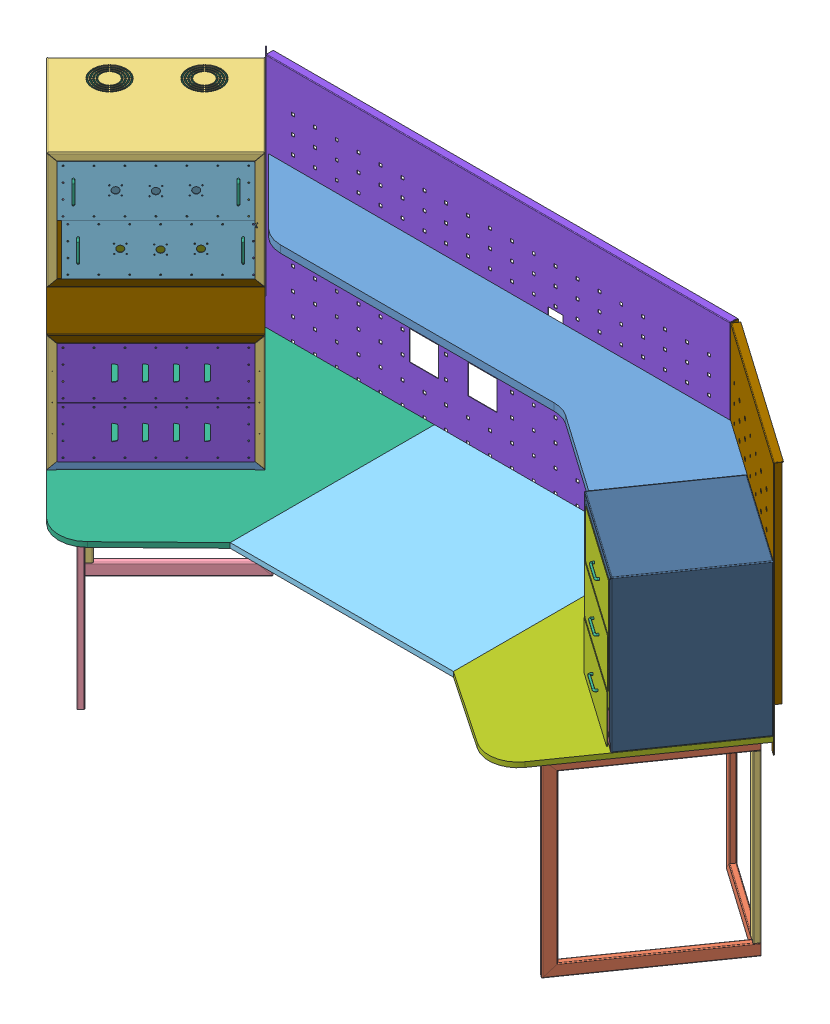
SolidWorks assembly ghép tổng, configuration Default. Lengths in mm.
Overall size (2623.8 1517 999.25).
65 component instances, 44 part files, 69 mates.
Components (placement in the parent):
- Assem chan trái-1: Assem chan trái [Default] at (-139.3246 124.9655 -27.3577) size (1329.02 40 864.99)
  - mặt bàn số 1-2: mặt bàn số 1 [Default<As Machined>] at (-327.0001 624.1073 994.183) size (1329.02 40 864.99)
  - ong giưa-4: ong giưa [Default<As Machined>] at (444.6829 644.1073 947.4494) x (0 0 1) z (-1 0 0) size (550 40 20)
- khung trái-1: khung trái [Default] at (-381.393 516.0492 385.0257) x (0 -1 0) z (-0.707107 0 0.707107) size (650 580 475)
  - ống chân-1: ống chân [Default<As Machined>] at (-193.0236 341.3386 471.4503) size (570 20 40)
  - chân số 1-1: chân số 1 [Default<As Machined>] at (376.9764 351.3386 471.4503) x (0 1 0) z (0 0 1) size (580 650 475)
- mặt bàn gỗ 1-2: mặt bàn gỗ 1 [Default] at (485.069 789.0728 1276.2616) size (765 17 700)
- mặt gỗ trái-2: mặt gỗ trái [Default] at (389.532 789.0728 1325.0917) size (954.77 17 970.55)
- mặt gỗ phải-2: mặt gỗ phải [Default] at (1154.532 789.0728 1325.0917) size (741.49 17 887.84)
- mặt sau trên-3: mặt sau trên [Default] at (607.032 749.0728 623.5917) x (-1 0 0) z (0 0 -1) size (1618.25 867 25.81)
- mặt phải tren-2: mặt phải tren [Default] at (1649.1305 749.0728 796.3614) x (0.819152 0 0.573576) z (-0.573576 0 0.819152) size (612.94 867 25)
- tủ phải chuan-2: tủ phải chuan [Default] at (2052.0607 760.4203 1059.043) x (-0.573576 0 0.819152) z (-0.819152 0 -0.573576) size (400 520 370)
  - ghép 1-1: ghép 1 [Default] at (144.53 45.6525 549.3287) size (400 520 370)
  - ghép 1 sau-1: ghép 1 sau [Default] at (15.935 45.6525 524.3287) x (0 0 -1) z (1 0 0) size (320 70 25)
  - doc phai-1: doc phai [Default] at (17.435 47.1525 180.8287) size (50 512 35)
  - ghep trước-5: ghep trước [Default] at (414.435 45.6525 549.3287) x (0 0 -1) z (1 0 0) size (370 25 25)
  - doc trai-1: doc trai [Default] at (17.435 559.1525 547.8287) x (1 0 0) z (0 0 -1) size (50 512 35)
  - doc trai  2-1: doc trai  2 [Default] at (414.435 47.1525 547.8287) x (-1 0 0) z (0 0 -1) size (50 514 35)
  - doc phai 2y-2: doc phai 2y [Default] at (414.435 561.1525 180.8287) x (-1 0 0) z (0 0 1) size (50 514 35)
  - nap sau-1: nap sau [Default] at (17.435 115.6525 364.3287) x (0 0 -1) z (1 0 0) size (320 370 10)
- Ghép tủ trái-1: Ghép tủ trái [Default] at (419.7096 736.1847 1334.931) x (-0.707107 0 0.707107) z (-0.707107 0 -0.707107) size (530 800 600)
  - tủ bên trái-1: tủ bên trái [Default] at (-46.2827 78.451 -28.8757) size (530 800 600)
    - năp hop ben trai-1: năp hop ben trai [Default] at (240.8112 391.4371 463.2686) x (-1 0 0) z (0 -1 0) size (530 202 48.5)
    - thanh nap truoc-1: thanh nap truoc [Default] at (505.8112 16.4371 362.2686) x (-1 0 0) z (0 0 1) size (530 25 25)
    - thanh nap sau-1: thanh nap sau [Default] at (0.8112 61.4371 962.2686) x (1 0 0) z (0 0 -1) size (480 70 25)
    - Tủ bên trái 29x9-2: Tủ bên trái 29x9 [Default] at (505.8112 391.4371 662.2686) size (530 800 600)
  - Thanh ngang 400-2: Thanh ngang 400 [Default] at (423.0241 608.0446 873.9814) x (0 1 0) z (-1 0 0) size (40 335 65)
  - Thanh doch 800 - phai-1: Thanh doch 800 - phai [Default] at (458.0285 861.3881 931.8929) x (0 0 -1) z (-1 0 0) size (50 790 35)
  - Thanh doch 800 trái-1: Thanh doch 800 trái [Default] at (-68.9715 71.3881 931.8929) x (0 0 -1) z (1 0 0) size (50 790 35)
  - Thanh ngang 400 - pahir-1: Thanh ngang 400 - pahir [Default] at (-54.9715 605.669 901.5877) x (0 1 0) z (-1 0 0) size (40 335 65)
  - Thanh dọc 400 - phai-1: Thanh dọc 400 - phai [Default] at (-68.9715 864.8881 534.8929) x (0 0 1) z (1 0 0) size (50 395 35)
  - Thanh dọc 400 trái-1: Thanh dọc 400 trái [Default] at (458.0285 469.8881 534.8929) x (0 0 1) z (-1 0 0) size (50 395 35)
  - Thanh dọc 400 d1-1: Thanh dọc 400 d1 [Default] at (458.0285 71.3881 334.8929) x (0 0 1) z (-1 0 0) size (50 392 35)
  - Thanh dọc 400 d2-1: Thanh dọc 400 d2 [Default] at (-68.9715 463.3881 334.8929) x (0 0 1) z (1 0 0) size (50 392 35)
  - Thanh nang 530-3: Thanh nang 530 [Default] at (446.0285 211.1086 900.198) x (0 1 0) z (-1 0 0) size (40 535 65)
  - Thanh nang 530 - phải-4: Thanh nang 530 - phải [Default] at (-54.9715 203.1166 901.5877) x (0 1 0) z (-1 0 0) size (40 535 65)
  - nap sau giua-1: nap sau giua [Default] at (194.5285 447.4566 933.3929) size (480 90 10)
  - nap sau tren-1: nap sau tren [Default] at (194.5285 537.4566 933.3929) size (480 307 10)
  - nap sau duoi-1: nap sau duoi [Default] at (193.5285 140.4566 933.3929) size (478 307 10)
- khay-1: khay [Default] at (234.5595 -371.0034 602.0103) size (1773.22 45 451.97)
  - khung khay-2: khung khay [Default] at (-78.6626 790.6632 -1209.4042) size (1740.21 20 412.89)
    - khung khay 1-1: khung khay 1 [Default<As Machined>] at (468.6351 881.4129 1232.4856) size (1740.21 20 412.89)
    - khung khay 2-5: khung khay 2 [Default<As Machined>] at (920.3643 871.4129 1252.4856) x (0 0 1) z (-1 0 0) size (160 20 20)
    - khung khay 2-7: khung khay 2 [Default<As Machined>] at (-57.1008 871.4129 1252.4856) x (0 0 1) z (-1 0 0) size (160 20 20)
  - mặt khay-2: mặt khay [Default] at (377.9726 1672.0761 23.0814) size (1773.22 25 451.97)
- chân 2Assem1-2: chân 2Assem1 [Default] at (2278.7361 40.1211 1323.9601) x (-0.574545 0 0.818473) z (-0.818473 0 -0.574545) size (540 650 670.82)
  - Chân thứ 2-1: Chân thứ 2 [Default<As Machined>] at (-34.1893 98.9516 617.8706) size (540 650 670.82)
  - chân số 2 30x09-1: chân số 2 30x09 [Default<As Machined>] at (-44.1893 383.9516 617.8706) x (0 -1 0) z (-1 0 0) size (570 40 20)
- mặt khung phải-2: mặt khung phải [Default] at (1063.5445 260.3297 185.6986) size (986.12 40 752.99)
  - mặt bàn số 2-1: mặt bàn số 2 [Default<As Machined>] at (-1500.9311 488.7431 703.8083) size (986.12 40 752.99)
  - ong giưa-1: ong giưa [Default<As Machined>] at (210.8644 508.7431 734.3931) x (0 0 1) z (-1 0 0) size (550 40 20)
- maumat1-1: maumat1 [Default] at (-93.5943 1493.5728 1096.7319) x (0.707107 0 -0.707107) z (0 1 0) size (480 2 175)
- maumat1-2: maumat1 [Default] at (-86.8768 1318.5728 1087.186) x (0.707107 0 -0.707107) z (0 1 0) size (480 2 175)
- tay cam-5: tay cam [Default] at (54.8981 1458.5728 962.3816) x (0 1 0) z (0.707107 0 0.707107) size (77 7 13.5)
- tay cam-6: tay cam [Default] at (-227.9446 1528.5728 1245.2243) x (0 -1 0) z (0.707107 0 0.707107) size (77 7 13.5)
- tay cam-8: tay cam [Default] at (-221.2271 1353.5728 1235.6784) x (0 -1 0) z (0.707107 0 0.707107) size (77 7 13.5)
- tay cam-9: tay cam [Default] at (61.6156 1353.5728 952.8357) x (0 -1 0) z (0.707107 0 0.707107) size (77 7 13.5)
- maumat2-2: maumat2 [Default] at (1513.9024 1218.5728 1192.425) x (0.819152 0 0.573576) z (0 1 0) size (320 2 165)
- maumat2-3: maumat2 [Default] at (1512.7553 1053.5728 1194.0633) x (0.819152 0 0.573576) z (0 1 0) size (320 2 165)
- maumat2-5: maumat2 [Default] at (1511.6081 888.5728 1195.7016) x (0.819152 0 0.573576) z (0 1 0) size (320 2 165)
- tay cam-11: tay cam [Default] at (1479.4963 1218.5728 1180.5414) x (0.819152 0 0.573576) z (-0.573576 0 0.819152) size (77 7 13.5)
- tay cam-12: tay cam [Default] at (1477.202 888.5728 1183.818) x (0.819152 0 0.573576) z (-0.573576 0 0.819152) size (77 7 13.5)
- tay cam-13: tay cam [Default] at (1478.3492 1053.5728 1182.1797) x (0.819152 0 0.573576) z (-0.573576 0 0.819152) size (77 7 13.5)
- mau mat-3: mau mat [Default] at (46.4128 918.5728 1236.7391) x (0.707107 0 -0.707107) z (0 -1 0) size (480 2 175)
- mau mat-4: mau mat [Default] at (47.827 1095.0728 1238.1533) x (0.707107 0 -0.707107) z (0 1 0) size (480 2 175)
Mates (geometry in assembly coordinates):
- Coincident1: coincident anti-aligned: plane of Assem chan trái-1/mặt bàn số 1-2 through (-468.446 749.0728 964.704) normal (0 -1 0); plane of khung trái-1/chân số 1-1 through (-184.8962 749.0728 661.3551) normal (0 1 0)
- Coincident2: coincident aligned: plane of Assem chan trái-1/mặt bàn số 1-2 through (-480.4669 752.0728 952.6831) normal (-0.707107 0 -0.707107); plane of khung trái-1/chân số 1-1 through (-187.0175 712.0728 659.2338) normal (-0.707107 0 -0.707107)
- Coincident3: coincident aligned: plane of Assem chan trái-1/mặt bàn số 1-2 through (14.5079 752.0728 1475.9422) normal (-0.707107 0 0.707107); plane of khung trái-1/chân số 1-1 through (-480.4669 712.0728 980.9674) normal (-0.707107 0 0.707107)
- Coincident34: coincident aligned: plane of Assem chan trái-1/mặt bàn số 1-2 through (-144.5911 752.0728 625.0917) normal (0 0 -1); plane of mặt bàn gỗ 1-2 through (389.532 806.0728 625.0917) normal (0 0 -1)
- Coincident35: coincident anti-aligned: plane of Assem chan trái-1/mặt bàn số 1-2 through (297.4797 789.0728 1197.213) normal (0 1 0); plane of mặt gỗ trái-2 through (71.9665 789.0728 1495.638) normal (0 -1 0)
- Coincident36: coincident anti-aligned: plane of mặt bàn gỗ 1-2 through (389.532 806.0728 625.0917) normal (-1 0 0); plane of mặt gỗ trái-2 through (389.532 806.0728 1325.0917) normal (1 0 0)
- Coincident37: coincident aligned: plane of Assem chan trái-1/mặt bàn số 1-2 through (-144.5911 752.0728 625.0917) normal (0 0 -1); plane of mặt gỗ trái-2 through (389.532 806.0728 625.0917) normal (0 0 -1)
- Coincident39: coincident anti-aligned: plane of mặt bàn gỗ 1-2 through (1154.532 806.0728 625.0917) normal (1 0 0); plane of mặt gỗ phải-2 through (1154.532 806.0728 1325.0917) normal (-1 0 0)
- Coincident49: coincident anti-aligned: plane of mặt bàn gỗ 1-2 through (389.532 806.0728 625.0917) normal (0 0 -1); plane of mặt sau trên-3 through (-190.468 1616.0728 625.0917) normal (0 0 1)
- Coincident50: coincident aligned: plane of Assem chan trái-1/mặt bàn số 1-2 through (-144.5911 749.0728 642.0917) normal (0 -1 0); plane of mặt sau trên-3 through (607.032 749.0728 623.5917) normal (0 -1 0)
- Coincident55: coincident aligned: line of mặt gỗ phải-2 through (1404.532 806.0728 625.0917) axis (0 -1 0); line of mặt sau trên-3 through (1404.532 898.3228 625.0917) axis (0 -1 0)
- Coincident56: coincident anti-aligned: plane of mặt sau trên-3 through (1404.532 749.0728 623.5917) normal (1 0 0); plane of mặt phải tren-2 through (1404.532 749.0728 797.7618) normal (-1 0 0)
- Coincident57: coincident aligned: plane of mặt sau trên-3 through (607.032 749.0728 623.5917) normal (0 -1 0); plane of mặt phải tren-2 through (1649.1305 749.0728 796.3614) normal (0 -1 0)
- Coincident58: coincident anti-aligned: plane of mặt gỗ phải-2 through (1404.532 806.0728 625.0917) normal (0.573576 0 -0.819152); plane of mặt phải tren-2 through (1894.8761 1616.0728 968.4343) normal (-0.573576 0 0.819152)
- Coincident59: coincident anti-aligned: plane of mặt phải tren-2 through (1894.8761 1616.0728 968.4343) normal (-0.573576 0 0.819152); plane of tủ phải chuan-2/ghép 1 sau-1 through (1613.4158 876.0728 771.3537) normal (0.573576 0 -0.819152)
- Coincident60: coincident anti-aligned: plane of mặt gỗ phải-2 through (1463.2674 806.0728 1412.9323) normal (0 1 0); plane of tủ phải chuan-2/ghep trước-5 through (1364.3668 806.0728 1083.4464) normal (0 -1 0)
- Coincident61: coincident aligned: plane of mặt gỗ phải-2 through (1896.0233 806.0728 969.2375) normal (0.819152 0 0.573576); plane of tủ phải chuan-2/ghép 1-1 through (1822.2643 806.0728 1074.5763) normal (0.819152 0 0.573576)
- Coincident62: coincident anti-aligned: plane of mặt gỗ trái-2 through (71.9665 806.0728 1495.638) normal (0 1 0); plane of Ghép tủ trái-1/tủ bên trái-1/Tủ bên trái 29x9-2 through (-353.1025 806.0728 1211.9903) normal (0 -1 0)
- Coincident63: coincident aligned: plane of Ghép tủ trái-1/tủ bên trái-1/Tủ bên trái 29x9-2 through (-565.2346 1206.0728 999.8583) normal (-0.707107 0 -0.707107); plane of mặt gỗ trái-2 through (-190.468 806.0728 625.0917) normal (-0.707107 0 -0.707107)
- Coincident64: coincident aligned: plane of mặt gỗ trái-2 through (-565.2346 806.0728 999.8583) normal (-0.707107 0 0.707107); plane of Ghép tủ trái-1/tủ bên trái-1/Tủ bên trái 29x9-2 through (-353.1025 1206.0728 1211.9903) normal (-0.707107 0 0.707107)
- Coincident65: coincident aligned: plane of tủ phải chuan-2/ghép 1-1 through (1519.178 1326.0728 862.3531) normal (0 1 0); plane of khay-1/mặt khay-2 through (111.9534 1326.0728 775.0917) normal (0 1 0)
- Coincident66: coincident anti-aligned: plane of mặt sau trên-3 through (-190.468 1616.0728 625.0917) normal (0 0 1); plane of khay-1/mặt khay-2 through (1404.532 1326.0728 625.0917) normal (0 0 -1)
- Coincident67: coincident anti-aligned: plane of mặt phải tren-2 through (1894.8761 1616.0728 968.4343) normal (-0.573576 0 0.819152); plane of khay-1/mặt khay-2 through (1404.532 1326.0728 625.0917) normal (0.573576 0 -0.819152)
- Coincident75: coincident anti-aligned: plane of mặt gỗ phải-2 through (1463.2674 789.0728 1412.9323) normal (0 -1 0); plane of mặt khung phải-2/mặt bàn số 2-1 through (1372.8793 789.0728 642.6363) normal (0 1 0)
- Coincident76: coincident anti-aligned: plane of mặt sau trên-3 through (-190.468 1616.0728 625.0917) normal (0 0 1); plane of mặt khung phải-2/mặt bàn số 2-1 through (854.4089 752.0728 625.0917) normal (0 0 -1)
- Coincident79: coincident anti-aligned: plane of chân 2Assem1-2/Chân thứ 2-1 through (1530.8015 749.0728 1343.6167) normal (0 1 0); plane of mặt khung phải-2/mặt bàn số 2-1 through (1795.1246 749.0728 942.7061) normal (0 -1 0)
- Coincident80: coincident aligned: plane of chân 2Assem1-2/Chân thứ 2-1 through (1804.16 712.0728 924.613) normal (0.574545 0 -0.818473); plane of mặt khung phải-2/mặt bàn số 2-1 through (1382.6465 752.0728 628.7222) normal (0.574545 0 -0.818473)
- Coincident81: coincident aligned: plane of chân 2Assem1-2/Chân thứ 2-1 through (1533.2569 712.0728 1345.3403) normal (0.818473 0 0.574545); plane of mặt khung phải-2/mặt bàn số 2-1 through (1809.0386 752.0728 952.4734) normal (0.818473 0 0.574545)
- Coincident83: coincident aligned: plane of Assem chan trái-1/mặt bàn số 1-2 through (817.4089 749.0728 645.0917) normal (0 -1 0); plane of mặt khung phải-2/mặt bàn số 2-1 through (851.4089 749.0728 1195.0917) normal (0 -1 0)
- Coincident84: coincident anti-aligned: plane of Assem chan trái-1/mặt bàn số 1-2 through (834.4089 752.0728 645.0917) normal (1 0 0); plane of mặt khung phải-2/mặt bàn số 2-1 through (834.4089 752.0728 1195.0917) normal (-1 0 0)
- Coincident85: coincident anti-aligned: plane of Ghép tủ trái-1/tủ bên trái-1/Tủ bên trái 29x9-2 through (-282.3918 1206.0728 1282.701) normal (0.707107 0 0.707107); plane of maumat1-1 through (72.5758 1578.0728 927.7334) normal (-0.707107 0 -0.707107)
- Coincident86: coincident anti-aligned: plane of Ghép tủ trái-1/tủ bên trái-1/Tủ bên trái 29x9-2 through (90.2534 1581.0728 910.0557) normal (0 -1 0); plane of maumat1-1 through (-262.5929 1581.0728 1262.902) normal (0 1 0)
- Coincident87: coincident anti-aligned: plane of Ghép tủ trái-1/tủ bên trái-1/Tủ bên trái 29x9-2 through (74.6971 1206.0728 925.6121) normal (-0.707107 0 0.707107); plane of maumat1-1 through (74.6971 1409.0728 925.6121) normal (0.707107 0 -0.707107)
- Coincident88: coincident aligned: plane of Ghép tủ trái-1/tủ bên trái-1/Tủ bên trái 29x9-2 through (-282.3918 1206.0728 1282.701) normal (0.707107 0 0.707107); plane of maumat1-2 through (80.7075 1403.0728 919.6017) normal (0.707107 0 0.707107)
- Coincident89: coincident anti-aligned: plane of Ghép tủ trái-1/tủ bên trái-1/năp hop ben trai-1 through (-283.8061 1231.0728 1281.2868) normal (0 1 0); plane of maumat1-2 through (-255.8753 1231.0728 1253.3561) normal (0 -1 0)
- Coincident90: coincident anti-aligned: plane of Ghép tủ trái-1/Thanh dọc 400 trái-1 through (-257.6431 1206.0728 1255.8309) normal (0.707107 0 -0.707107); plane of maumat1-2 through (-257.9967 1234.0728 1255.4774) normal (-0.707107 0 0.707107)
- Coincident95: coincident aligned: circle of maumat1-1; circle of tay cam-6
- Coincident98: coincident aligned: circle of maumat1-1; circle of tay cam-6
- Coincident99: coincident aligned: circle of maumat1-1; circle of tay cam-5
- Coincident100: coincident aligned: circle of maumat1-1; circle of tay cam-5
- Coincident101: coincident aligned: circle of maumat1-2; circle of tay cam-8
- Concentric5: concentric anti-aligned: cylinder of maumat1-2 through (-229.7124 1283.5728 1227.1931) axis (0.707107 0 0.707107) radius 2; cylinder of tay cam-8 through (-226.884 1283.5728 1230.0215) axis (-0.707107 0 -0.707107) radius 2
- Coincident102: coincident aligned: circle of maumat1-2; circle of tay cam-9
- Coincident103: coincident aligned: circle of maumat1-2; circle of tay cam-9
- Coincident104: coincident aligned: plane of mặt bàn gỗ 1-2 through (485.069 806.0728 1276.2616) normal (0 1 0); plane of mặt gỗ phải-2 through (1463.2674 806.0728 1412.9323) normal (0 1 0)
- Coincident109: coincident anti-aligned: plane of tủ phải chuan-2/ghép 1-1 through (1363.5064 806.0728 1084.6751) normal (-0.573576 0 0.819152); plane of maumat2-2 through (1387.2618 1297.0728 1101.3088) normal (0.573576 0 -0.819152)
- Coincident110: coincident anti-aligned: plane of tủ phải chuan-2/ghép 1-1 through (1664.1352 1301.0728 1295.1776) normal (0 -1 0); plane of maumat2-2 through (1387.2618 1301.0728 1101.3088) normal (0 1 0)
- Coincident111: coincident anti-aligned: plane of tủ phải chuan-2/ghép 1-1 through (1383.9852 806.0728 1099.0145) normal (0.819152 0 0.573576); plane of maumat2-2 through (1383.9852 1140.0728 1099.0145) normal (-0.819152 0 -0.573576)
- Coincident112: coincident anti-aligned: plane of maumat2-2 through (1386.1147 1297.0728 1102.9471) normal (-0.573576 0 0.819152); plane of maumat2-3 through (1386.1147 1132.0728 1102.9471) normal (0.573576 0 -0.819152)
- Coincident113: coincident anti-aligned: plane of tủ phải chuan-2/ghép 1-1 through (1383.9852 806.0728 1099.0145) normal (0.819152 0 0.573576); plane of maumat2-3 through (1382.8381 975.0728 1100.6528) normal (-0.819152 0 -0.573576)
- Coincident114: coincident anti-aligned: plane of maumat2-2 through (1387.2618 1136.0728 1101.3088) normal (0 -1 0); plane of maumat2-3 through (1386.1147 1136.0728 1102.9471) normal (0 1 0)
- Coincident119: coincident anti-aligned: plane of maumat2-3 through (1384.9675 1132.0728 1104.5854) normal (-0.573576 0 0.819152); plane of maumat2-5 through (1384.9675 967.0728 1104.5854) normal (0.573576 0 -0.819152)
- Coincident120: coincident anti-aligned: plane of maumat2-3 through (1386.1147 971.0728 1102.9471) normal (0 -1 0); plane of maumat2-5 through (1384.9675 971.0728 1104.5854) normal (0 1 0)
- Coincident121: coincident anti-aligned: plane of tủ phải chuan-2/ghép 1-1 through (1646.1139 806.0728 1282.559) normal (-0.819152 0 -0.573576); plane of maumat2-5 through (1643.8196 810.0728 1285.8356) normal (0.819152 0 0.573576)
- Concentric7: concentric anti-aligned: cylinder of maumat2-2 through (1486.3792 1218.5728 1170.7116) axis (-0.573576 0 0.819152) radius 2; cylinder of tay cam-11 through (1484.0849 1218.5728 1173.9882) axis (0.573576 0 -0.819152) radius 2
- Concentric8: concentric anti-aligned: cylinder of maumat2-2 through (1543.7199 1218.5728 1210.8619) axis (-0.573576 0 0.819152) radius 2; cylinder of tay cam-11 through (1541.4256 1218.5728 1214.1385) axis (0.573576 0 -0.819152) radius 2
- Coincident123: coincident anti-aligned: plane of maumat2-2 through (1386.1147 1297.0728 1102.9471) normal (-0.573576 0 0.819152); plane of tay cam-11 through (1485.2321 1218.5728 1172.3499) normal (0.573576 0 -0.819152)
- Concentric9: concentric anti-aligned: cylinder of maumat2-3 through (1485.2321 1053.5728 1172.3499) axis (-0.573576 0 0.819152) radius 2; cylinder of tay cam-13 through (1482.9378 1053.5728 1175.6265) axis (0.573576 0 -0.819152) radius 2
- Concentric10: concentric anti-aligned: cylinder of maumat2-3 through (1542.5727 1053.5728 1212.5002) axis (-0.573576 0 0.819152) radius 2; cylinder of tay cam-13 through (1540.2784 1053.5728 1215.7768) axis (0.573576 0 -0.819152) radius 2
- Coincident124: coincident anti-aligned: plane of maumat2-3 through (1384.9675 1132.0728 1104.5854) normal (-0.573576 0 0.819152); plane of tay cam-13 through (1484.0849 1053.5728 1173.9882) normal (0.573576 0 -0.819152)
- Concentric11: concentric anti-aligned: cylinder of maumat2-5 through (1484.0849 888.5728 1173.9882) axis (-0.573576 0 0.819152) radius 2; cylinder of tay cam-12 through (1481.7906 888.5728 1177.2648) axis (0.573576 0 -0.819152) radius 2
- Coincident125: coincident anti-aligned: cylinder of maumat2-5 through (1541.4256 888.5728 1214.1385) axis (-0.573576 0 0.819152) radius 2; circle of tay cam-12
- Coincident126: coincident anti-aligned: plane of maumat2-5 through (1383.8204 967.0728 1106.2237) normal (-0.573576 0 0.819152); plane of tay cam-12 through (1540.2784 888.5728 1215.7768) normal (0.573576 0 -0.819152)
- Coincident127: coincident anti-aligned: plane of Ghép tủ trái-1/tủ bên trái-1/năp hop ben trai-1 through (46.4128 1206.0728 1236.7391) normal (0.707107 0 0.707107); plane of mau mat-4 through (213.9971 1179.5728 1069.1547) normal (-0.707107 0 -0.707107)
- Coincident128: coincident anti-aligned: plane of Ghép tủ trái-1/tủ bên trái-1/Tủ bên trái 29x9-2 through (216.1184 806.0728 1067.0334) normal (-0.707107 0 0.707107); plane of mau mat-4 through (216.1184 1010.5728 1067.0334) normal (0.707107 0 -0.707107)
- Coincident129: coincident anti-aligned: plane of Ghép tủ trái-1/tủ bên trái-1/năp hop ben trai-1 through (233.7961 1182.5728 1049.3558) normal (0 -1 0); plane of mau mat-4 through (-121.1715 1182.5728 1404.3234) normal (0 1 0)
- Coincident131: coincident anti-aligned: plane of Ghép tủ trái-1/tủ bên trái-1/Tủ bên trái 29x9-2 through (216.1184 806.0728 1067.0334) normal (-0.707107 0 0.707107); plane of mau mat-3 through (217.5327 1003.0728 1068.4476) normal (0.707107 0 -0.707107)
- Coincident132: coincident anti-aligned: plane of Ghép tủ trái-1/tủ bên trái-1/thanh nap truoc-1 through (-140.9705 831.0728 1424.1224) normal (0 1 0); plane of mau mat-3 through (-119.7573 831.0728 1405.7376) normal (0 -1 0)
- Coincident134: coincident aligned: plane of mau mat-3 through (215.4113 834.0728 1070.569) normal (0.707107 0 0.707107); plane of mau mat-4 through (215.4113 1179.5728 1070.569) normal (0.707107 0 0.707107)
